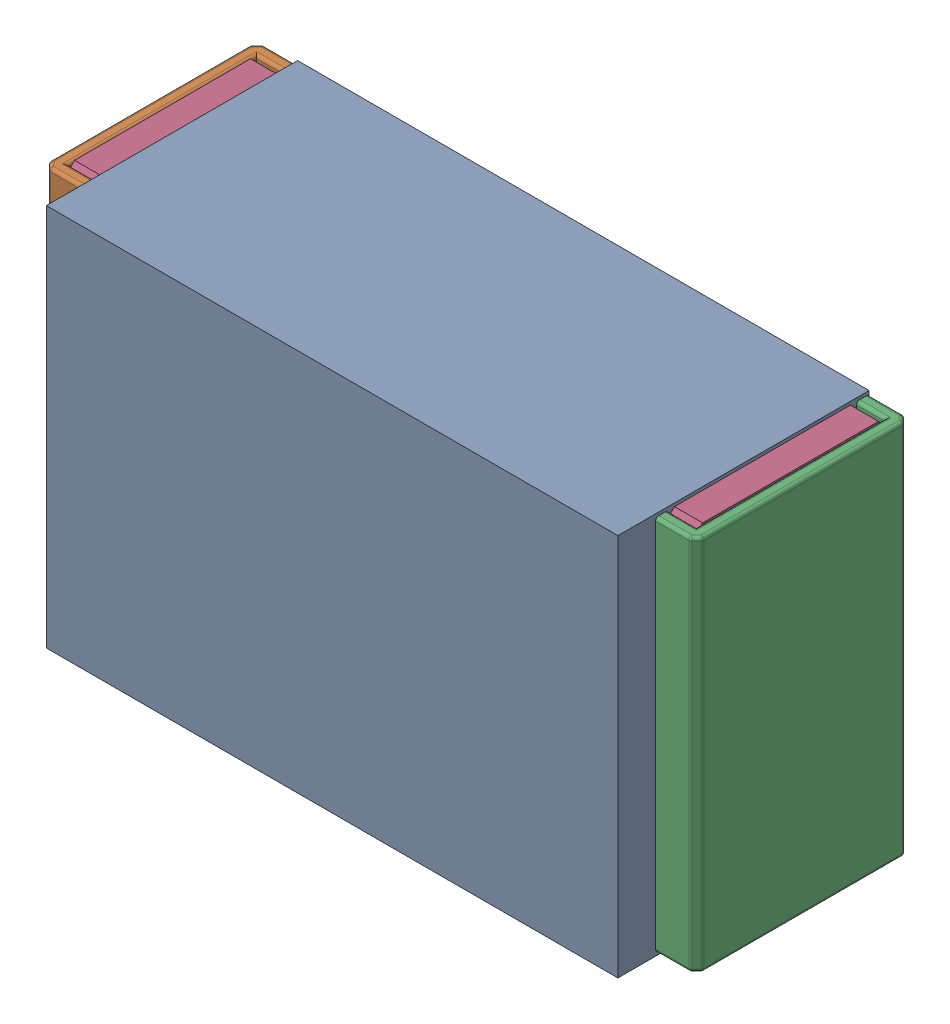
SolidWorks assembly R2, configuration Default. Lengths in mm.
Overall size (1.04 0.61 0.4).
3 component instances, 2 part files, 0 mates.
Components (placement in the parent):
- 1088880352-1: 1088880352 [Default] at (4.6 42.975 0) size (0.91 0.61 0.4)
  - Extruded-28-1: Extruded-28 [Default] at origin size (0.91 0.61 0.4)
- R0402-1: R0402 [Default] at (4.6 42.975 0) x (-1 0 0) z (0 1 0) size (1.04 0.34 0.6)
